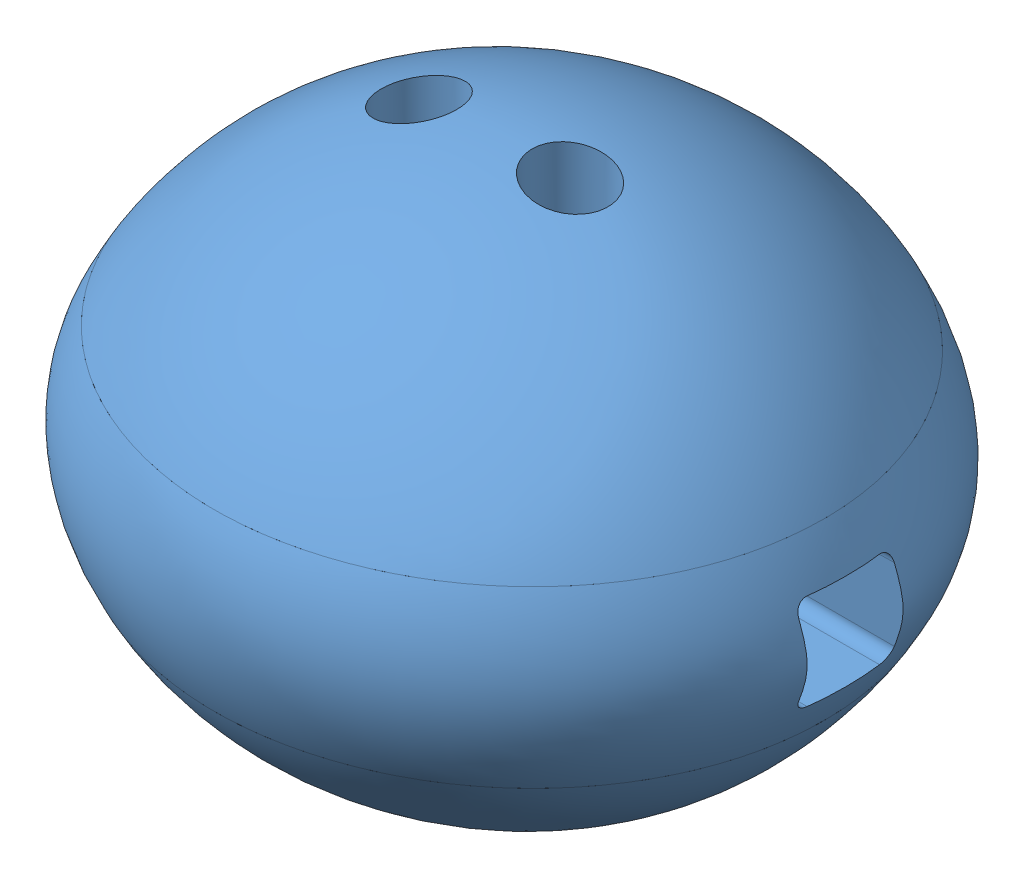
SolidWorks assembly Ballast_Weight_Assembly, configuration Default. Lengths in mm.
Overall size (152.07 114.4 139.83).
7 component instances, 3 part files, 14 mates.
Components (placement in the parent):
- Ballast_Weight-1: Ballast_Weight [Default] at origin size (152.07 114.4 139.83)
- Ballast_Weight-2: Ballast_Weight [Ballast Weight Outside] at origin size (144.63 51.5 137.25)
- Ballast_Weight-3: Ballast_Weight [Ballast Weight Outside] x (1 0 0) z (0 0 -1) size (144.63 51.5 137.25)
- 92196A554_18-8 STAINLESS STEEL SOCKET HEAD CAP SCREW-1: 92196A554_18-8 STAINLESS STEEL SOCKET HEAD CAP SCREW [92196A554] at (12.7 41.275 0) x (1 0 0) z (0 1 0) size (9.53 9.53 83.33)
- 92196A554_18-8 STAINLESS STEEL SOCKET HEAD CAP SCREW-2: 92196A554_18-8 STAINLESS STEEL SOCKET HEAD CAP SCREW [92196A554] at (-20.32 41.275 0) x (0.947644 0 -0.319328) z (0 1 0) size (9.53 9.53 83.33)
- 92673A113_ASTM F594 TYPE 18-8 STAINLESS STEEL HEX NUT-2: 92673A113_ASTM F594 TYPE 18-8 STAINLESS STEEL HEX NUT [92673A113] at (-20.32 37.7031 0) x (1 0 0) z (0 1 0) size (11.11 12.83 6.51)
- 92673A113_ASTM F594 TYPE 18-8 STAINLESS STEEL HEX NUT-3: 92673A113_ASTM F594 TYPE 18-8 STAINLESS STEEL HEX NUT [92673A113] at (12.7 37.7031 0) x (0.939231 0 0.343287) z (0 1 0) size (11.11 12.83 6.51)
Mates (geometry in assembly coordinates):
- Coincident3: coordinate: point of ?
- Coincident13: coincident anti-aligned: plane of Ballast_Weight-1 through (-76.2 19.05 -101.6) normal (0 1 0); plane of Ballast_Weight-2 through (-76.2018 19.05 -101.6) normal (0 -1 0)
- Coincident14: coincident aligned: plane of Ballast_Weight-2 through (0 0 0) normal (0 0 1); plane of assembly through (0 0 0) normal (0 0 1)
- Coincident15: coincident aligned: plane of Ballast_Weight-2 through (0 0 0) normal (1 0 0); plane of assembly through (0 0 0) normal (1 0 0)
- Coincident17: coincident anti-aligned: plane of Ballast_Weight-1 through (-76.2 -19.05 -101.6) normal (0 -1 0); plane of Ballast_Weight-3 through (-76.2018 -19.05 101.6) normal (0 1 0)
- Concentric1: concentric anti-aligned: cylinder of Ballast_Weight-1 through (-20.32 0 0) axis (0 -1 0) radius 3.3782; cylinder of Ballast_Weight-3 through (-20.32 0 0) axis (0 1 0) radius 3.2639
- Concentric3: concentric anti-aligned: cylinder of Ballast_Weight-1 through (12.7 0 0) axis (0 -1 0) radius 3.3782; cylinder of 92196A554_18-8 STAINLESS STEEL SOCKET HEAD CAP SCREW-1 through (12.7 -34.925 0) axis (0 1 0) radius 3.175
- Coincident18: coincident anti-aligned: plane of Ballast_Weight-3 through (12.7 -34.925 0) normal (0 -1 0); plane of 92196A554_18-8 STAINLESS STEEL SOCKET HEAD CAP SCREW-1 through (12.7 -34.925 0) normal (0 1 0)
- Concentric6: concentric anti-aligned: cylinder of Ballast_Weight-1 through (-20.32 0 0) axis (0 -1 0) radius 3.3782; cylinder of 92196A554_18-8 STAINLESS STEEL SOCKET HEAD CAP SCREW-2 through (-20.32 -34.925 0) axis (0 1 0) radius 3.175
- Coincident21: coincident anti-aligned: plane of Ballast_Weight-3 through (-20.32 -34.925 0) normal (0 -1 0); plane of 92196A554_18-8 STAINLESS STEEL SOCKET HEAD CAP SCREW-2 through (-20.32 -34.925 0) normal (0 1 0)
- Coincident22: coincident anti-aligned: cylinder of 92196A554_18-8 STAINLESS STEEL SOCKET HEAD CAP SCREW-1 through (12.7 -34.925 0) axis (0 1 0) radius 3.175; circle of 92673A113_ASTM F594 TYPE 18-8 STAINLESS STEEL HEX NUT-3
- Coincident23: coincident anti-aligned: circle of Ballast_Weight-2; plane of 92673A113_ASTM F594 TYPE 18-8 STAINLESS STEEL HEX NUT-3 through (8.5826 34.925 -4.9203) normal (0 -1 0)
- Coincident24: coincident anti-aligned: cylinder of 92196A554_18-8 STAINLESS STEEL SOCKET HEAD CAP SCREW-2 through (-20.32 -34.925 0) axis (0 1 0) radius 3.175; circle of 92673A113_ASTM F594 TYPE 18-8 STAINLESS STEEL HEX NUT-2
- Coincident25: coincident anti-aligned: circle of Ballast_Weight-2; plane of 92673A113_ASTM F594 TYPE 18-8 STAINLESS STEEL HEX NUT-2 through (-25.8762 34.925 -3.2079) normal (0 -1 0)
